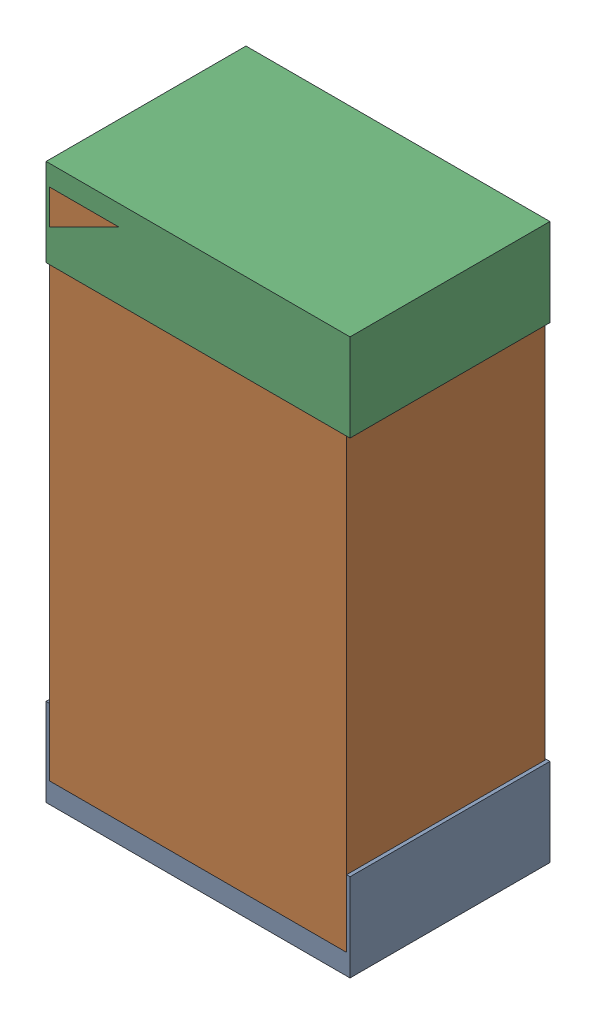
SolidWorks assembly R30Kanaloa_v2.0.0_Motor, configuration Default. Lengths in mm.
Overall size (1.3 2.38 0.85).
6 component instances, 2 part files, 0 mates.
Components (placement in the parent):
- 330415056-1: 330415056 [Default] at (127 98.568 -1.9574) size (1.3 0.38 0.85)
  - Extruded_2-1: Extruded_2 [Default] at origin size (1.3 0.38 0.85)
- 334787376-1: 334787376 [Default] at (127 99.568 -1.9524) size (1.27 2.2 0.85)
  - Extruded_16-1: Extruded_16 [Default] at origin size (1.27 2.2 0.85)
- 330415056-2: 330415056 [Default] at (127 100.568 -1.9574) size (1.3 0.38 0.85)
  - Extruded_2-1: Extruded_2 [Default] at origin size (1.3 0.38 0.85)
